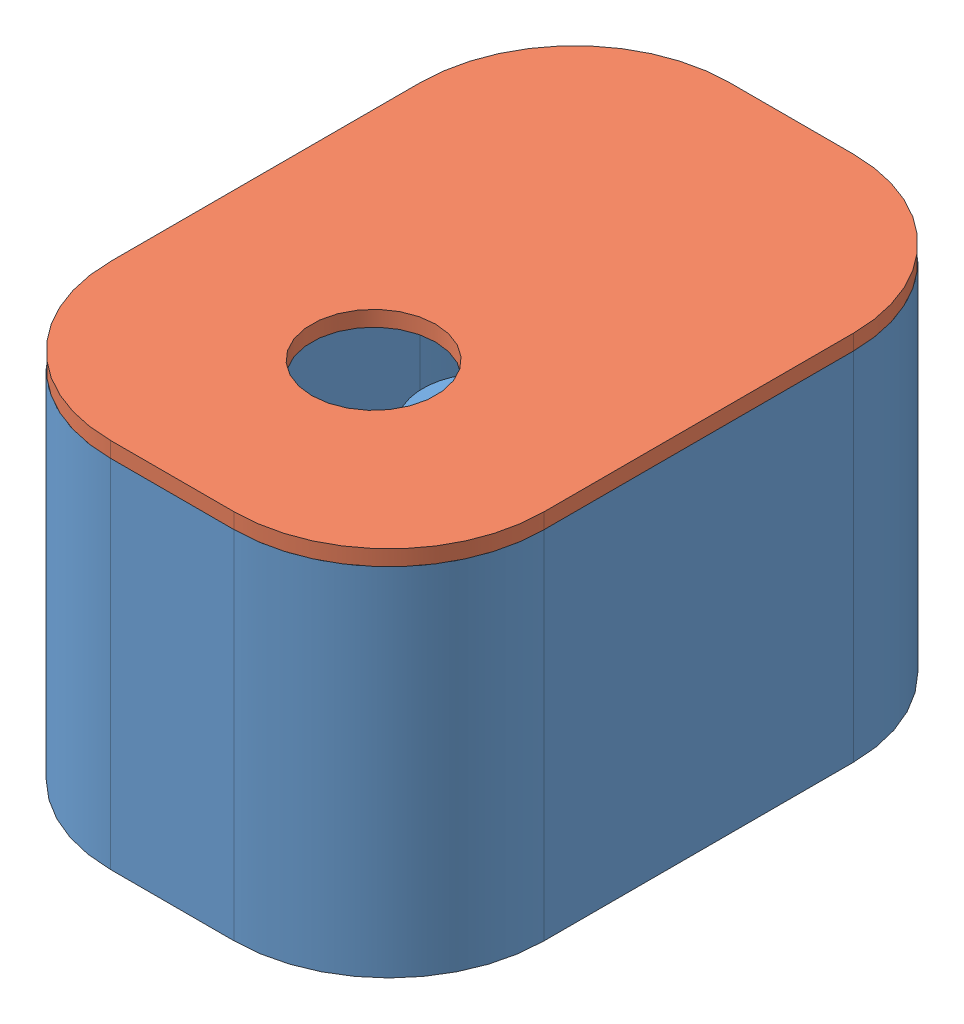
SolidWorks assembly Assem1, configuration Default. Lengths in mm.
Overall size (28 24 40).
2 component instances, 2 part files, 3 mates.
Components (placement in the parent):
- base_v2-1: base_v2 [Default] at (17.2246 14.1143 35.3109) size (28 23 40)
- cap_v2-1: cap_v2 [Default] at (17.2246 34.1143 35.3109) x (-1 0 0) z (0 0 1) size (28 3 40)
Mates (geometry in assembly coordinates):
- Coincident1: coincident: plane of base_v2-1 through (28.7246 24.1143 35.3109) normal (-1 0 0); plane of ? through (28.7246 33.6075 35.3109) normal (1 0 0)
- Coincident2: coincident: plane of base_v2-1 through (17.2246 24.1143 45.8109) normal (0 0 -1); plane of ? through (17.2246 33.6075 45.8109) normal (0 0 1)
- Coincident3: coincident: plane of assembly; plane of assembly; plane of base_v2-1 through (17.2246 34.1143 35.3109) normal (0 1 0); plane of cap_v2-1 through (17.2246 34.1143 35.3109) normal (0 -1 0)
